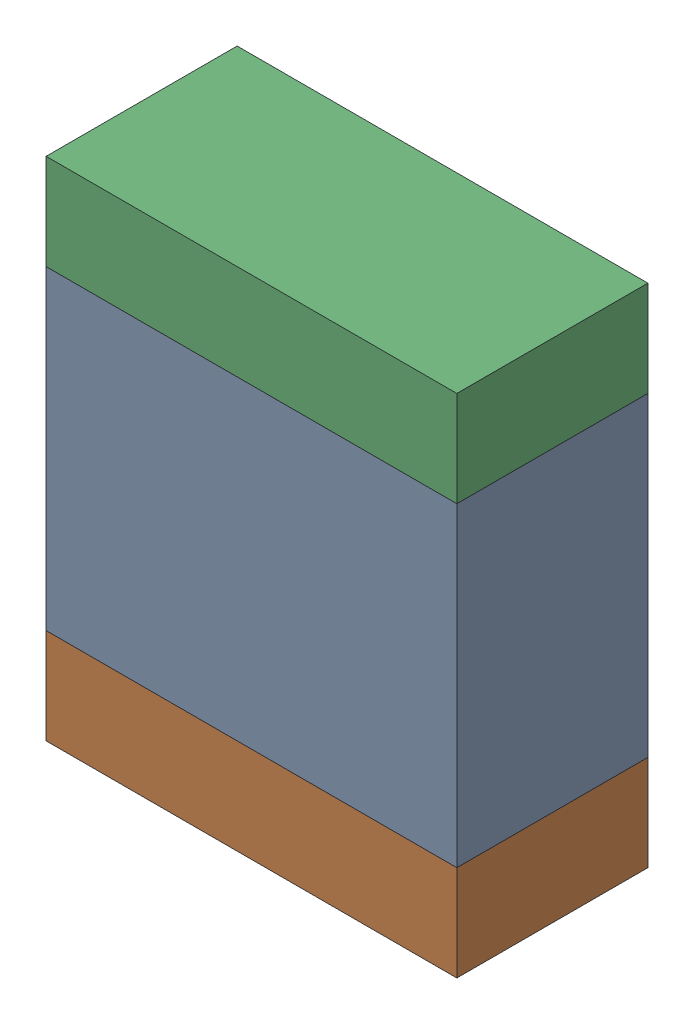
SolidWorks assembly L400PCB, configuration Default. Lengths in mm.
Overall size (2.15 2.65 1).
6 component instances, 2 part files, 0 mates.
Components (placement in the parent):
- 846484648-1: 846484648 [Default] at (93.2 79.7 -2.6638) size (2.15 1.65 1)
  - Extruded_43-1: Extruded_43 [Default] at origin size (2.15 1.65 1)
- 846484784-1: 846484784 [Default] at (93.2 78.625 -2.6638) size (2.15 0.5 1)
  - Extruded_44-1: Extruded_44 [Default] at origin size (2.15 0.5 1)
- 846484784-2: 846484784 [Default] at (93.2 80.775 -2.6638) size (2.15 0.5 1)
  - Extruded_44-1: Extruded_44 [Default] at origin size (2.15 0.5 1)
